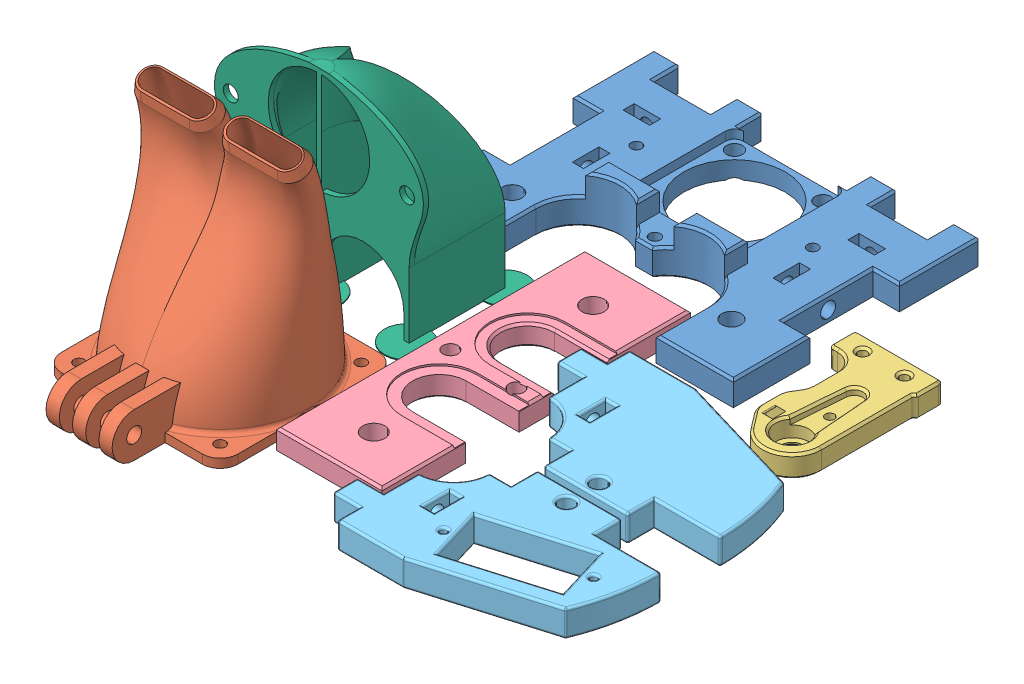
SolidWorks assembly IttyBittyDoublePlate1, configuration Default. Lengths in mm.
Overall size (185 51.83 185).
7 component instances, 6 part files, 15 mates.
Components (placement in the parent):
- XCarriageDoubleShelf-1: XCarriageDoubleShelf [Default] at (32.4491 6 -16.5271) x (-1 0 0) z (0 0 1) size (74 10.95 56)
- PartCoolingDoubleFanShroud-1: PartCoolingDoubleFanShroud [Default] at (-33.1683 0 34.2818) x (-1 0 0) z (0 0 -1) size (41.23 51.54 53.9)
- ZProbeArmMirrored-1: ZProbeArmMirrored [Default] at (61.9129 8.5669 -12.4837) x (0 0 -1) z (-1 0 0) size (33.66 4.95 19.95)
- DoubleGrooveMount-1: DoubleGrooveMount [Default] at (0.9388 5 8.6538) x (0 0 -1) z (-1 0 0) size (70 5.31 24)
- ServoShelfBracket-1: ServoShelfBracket [Hot End Wiring Vent] at (14.799 0 15.8269) x (1 0 0) z (0 -1 0) size (53 32.5 6)
- ServoShelfBracket-2: ServoShelfBracket [HXT900] at (15.0398 6 29.4143) x (1 0 0) z (0 1 0) size (53 32.5 6)
- TightDoubleHexagonShroud-1: TightDoubleHexagonShroud [With Support] at (-37.7653 44.05 7.2698) x (-1 0 0) z (0 -1 0) size (57.71 31.8 44.86)
Mates (geometry in assembly coordinates):
- Coincident1: coincident anti-aligned: plane of XCarriageDoubleShelf-1 through (32.4491 0 -16.5271) normal (0 -1 0); plane of assembly through (0 0 0) normal (0 1 0)
- Parallel1: parallel aligned: plane of XCarriageDoubleShelf-1 through (32.4491 0 -16.5271) normal (0 0 1); plane of assembly through (0 0 0) normal (0 0 1)
- Coincident3: coincident anti-aligned: plane of ServoShelfBracket-2 through (15.0398 0 29.4143) normal (0 -1 0); plane of assembly through (0 0 0) normal (0 1 0)
- Coincident4: coincident anti-aligned: plane of ServoShelfBracket-1 through (14.799 0 15.8269) normal (0 -1 0); plane of assembly through (0 0 0) normal (0 1 0)
- Coincident5: coincident anti-aligned: plane of ZProbeArmMirrored-1 through (61.9129 0 -12.4837) normal (0 -1 0); plane of assembly through (0 0 0) normal (0 1 0)
- Coincident6: coincident anti-aligned: plane of DoubleGrooveMount-1 through (0.9388 0 8.6538) normal (0 -1 0); plane of assembly through (0 0 0) normal (0 1 0)
- Coincident7: coincident anti-aligned: plane of PartCoolingDoubleFanShroud-1 through (-33.1683 0 34.2818) normal (0 -1 0); plane of assembly through (0 0 0) normal (0 1 0)
- Parallel2: parallel anti-aligned: plane of DoubleGrooveMount-1 through (-11.0612 0 8.6538) normal (-1 0 0); plane of assembly through (0 0 0) normal (1 0 0)
- Parallel3: parallel anti-aligned: plane of XCarriageDoubleShelf-1 through (-41.5509 0 -16.5271) normal (-1 0 0); plane of assembly through (0 0 0) normal (1 0 0)
- Parallel4: parallel aligned: plane of ZProbeArmMirrored-1 through (54.6575 0 -12.4837) normal (1 0 0); plane of assembly through (0 0 0) normal (1 0 0)
- Parallel5: parallel anti-aligned: plane of ServoShelfBracket-1 through (8.799 0 15.8269) normal (-1 0 0); plane of assembly through (0 0 0) normal (1 0 0)
- Parallel6: parallel anti-aligned: plane of ServoShelfBracket-2 through (9.0398 6 29.4143) normal (-1 0 0); plane of assembly through (0 0 0) normal (1 0 0)
- Parallel7: parallel: line of PartCoolingDoubleFanShroud-1 through (-53.1683 0 50.2818) axis (0 0 -1); plane of assembly
- Parallel8: parallel aligned: plane of TightDoubleHexagonShroud-1 through (-37.7653 44.05 7.2698) normal (0 0 1); plane of assembly through (0 0 0) normal (0 0 1)
- Coincident9: coincident anti-aligned: plane of TightDoubleHexagonShroud-1 through (-37.7653 0 7.2698) normal (0 -1 0); plane of assembly through (0 0 0) normal (0 1 0)
